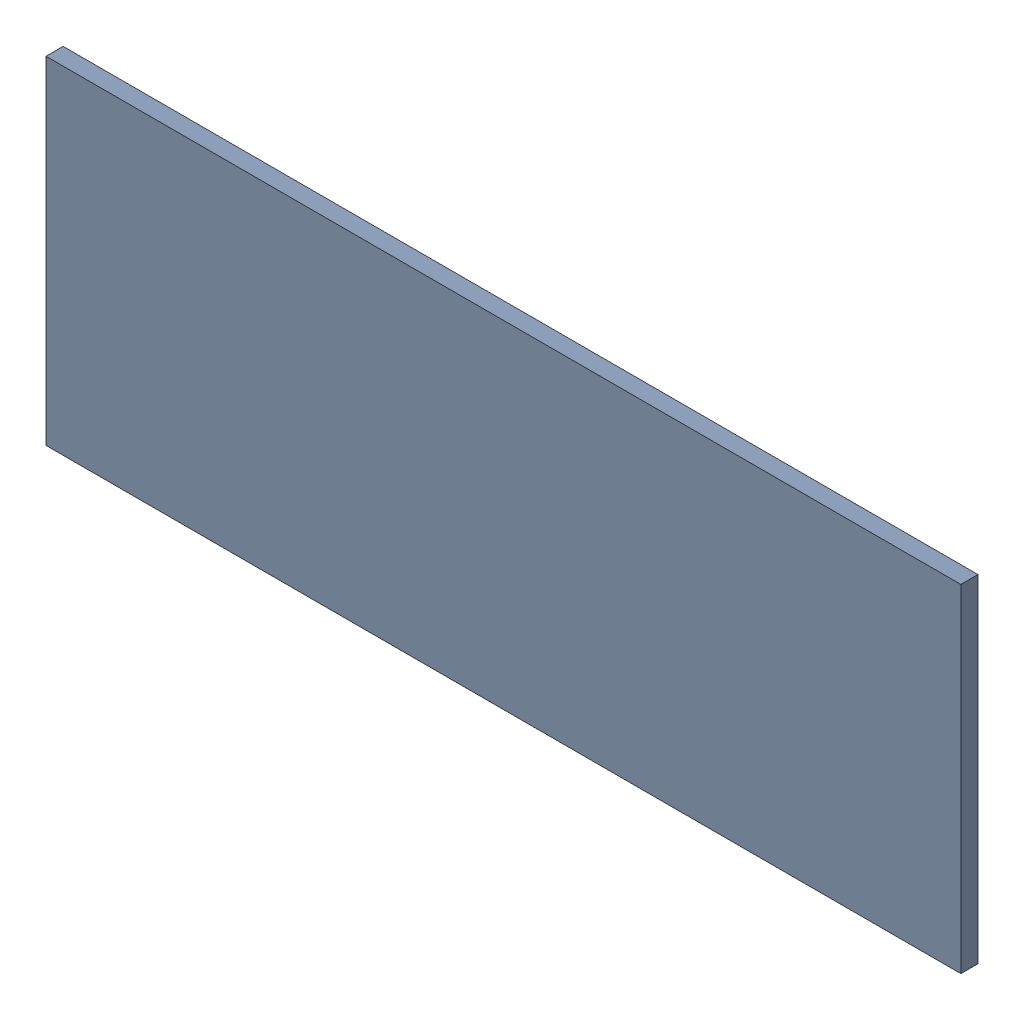
SolidWorks assembly Pad RAK4600-25(29.2mm,16.25mm) on Top Layer, configuration Predeterminado. Lengths in mm.
Overall size (1.9 0.7 0.04).
2 component instances, 1 part files, 0 mates.
Components (placement in the parent):
- Pad RAK4600-25(29.2mm,16.25mm) on Top Layer-1-1: Pad RAK4600-25(29.2mm,16.25mm) on Top Layer-1 [Predeterminado] at (-68.317 -44.187 -0.0457) size (1.9 0.7 0.04)
  - Pad RAK4600-25(29.2mm,16.25mm) on Top Layer-Part-1-1: Pad RAK4600-25(29.2mm,16.25mm) on Top Layer-Part-1 [Predeterminado] at origin size (1.9 0.7 0.04)
